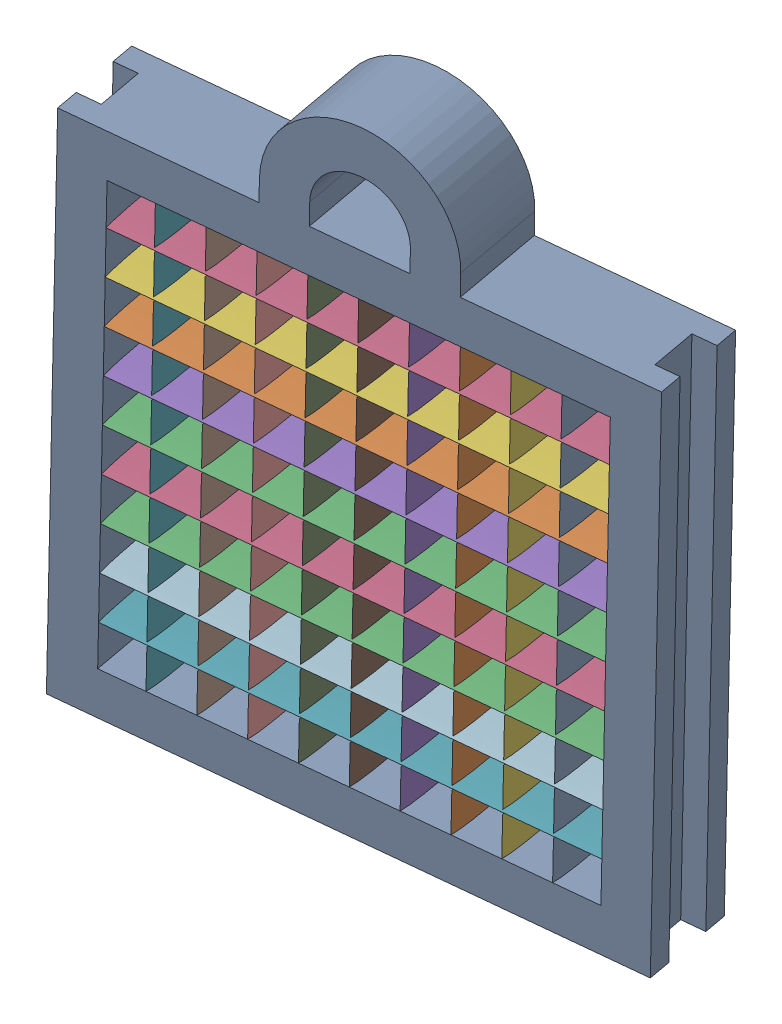
SolidWorks assembly Blade_assembly-2, configuration Default. Lengths in mm.
Overall size (128.96 151.07 42.39).
19 component instances, 2 part files, 0 mates.
Components (placement in the parent):
- Blade Frame-1-1: Blade Frame-1 [Default] at (771.0253 -161.3106 -497.9575) x (-0.987316 0.046404 0.151832) z (-0.150148 0.037854 -0.987939) size (120 145 20)
- Blade Piece-1-1: Blade Piece-1 [Default] at (675.8845 -87.1952 -480.658) x (0.051592 0.998205 0.030407) z (-0.150148 0.037854 -0.987939) size (1 100 20)
- Blade Piece-1-2: Blade Piece-1 [Default] at (674.8423 -107.3589 -481.2722) x (0.051592 0.998205 0.030407) z (-0.150148 0.037854 -0.987939) size (1 100 20)
- Blade Piece-1-3: Blade Piece-1 [Default] at (674.3212 -117.4408 -481.5793) x (0.051592 0.998205 0.030407) z (-0.150148 0.037854 -0.987939) size (1 100 20)
- Blade Piece-1-4: Blade Piece-1 [Default] at (731.1377 -159.4359 -491.8235) x (0.987316 -0.046404 -0.151832) z (0.150148 -0.037854 0.987939) size (1 100 20)
- Blade Piece-1-5: Blade Piece-1 [Default] at (676.4055 -77.1133 -480.3509) x (0.051592 0.998205 0.030407) z (-0.150148 0.037854 -0.987939) size (1 100 20)
- Blade Piece-1-6: Blade Piece-1 [Default] at (672.758 -147.6864 -482.5007) x (0.051592 0.998205 0.030407) z (-0.150148 0.037854 -0.987939) size (1 100 20)
- Blade Piece-1-7: Blade Piece-1 [Default] at (691.2502 -157.5612 -485.6895) x (0.987316 -0.046404 -0.151832) z (0.150148 -0.037854 0.987939) size (1 100 20)
- Blade Piece-1-8: Blade Piece-1 [Default] at (711.1939 -158.4986 -488.7565) x (0.987316 -0.046404 -0.151832) z (0.150148 -0.037854 0.987939) size (1 100 20)
- Blade Piece-1-9: Blade Piece-1 [Default] at (701.2221 -158.0299 -487.223) x (0.987316 -0.046404 -0.151832) z (0.150148 -0.037854 0.987939) size (1 100 20)
- Blade Piece-1-10: Blade Piece-1 [Default] at (721.1658 -158.9672 -490.29) x (0.987316 -0.046404 -0.151832) z (0.150148 -0.037854 0.987939) size (1 100 20)
- Blade Piece-1-11: Blade Piece-1 [Default] at (673.2791 -137.6045 -482.1935) x (0.051592 0.998205 0.030407) z (-0.150148 0.037854 -0.987939) size (1 100 20)
- Blade Piece-1-12: Blade Piece-1 [Default] at (761.0534 -160.8419 -496.424) x (0.987316 -0.046404 -0.151832) z (0.150148 -0.037854 0.987939) size (1 100 20)
- Blade Piece-1-13: Blade Piece-1 [Default] at (741.1096 -159.9046 -493.357) x (0.987316 -0.046404 -0.151832) z (0.150148 -0.037854 0.987939) size (1 100 20)
- Blade Piece-1-14: Blade Piece-1 [Default] at (673.8002 -127.5226 -481.8864) x (0.051592 0.998205 0.030407) z (-0.150148 0.037854 -0.987939) size (1 100 20)
- Blade Piece-1-15: Blade Piece-1 [Default] at (676.9266 -67.0314 -480.0438) x (0.051592 0.998205 0.030407) z (-0.150148 0.037854 -0.987939) size (1 100 20)
- Blade Piece-1-16: Blade Piece-1 [Default] at (675.3634 -97.277 -480.9651) x (0.051592 0.998205 0.030407) z (-0.150148 0.037854 -0.987939) size (1 100 20)
- Blade Piece-1-17: Blade Piece-1 [Default] at (751.0815 -160.3733 -494.8905) x (0.987316 -0.046404 -0.151832) z (0.150148 -0.037854 0.987939) size (1 100 20)
- Blade Piece-1-18: Blade Piece-1 [Default] at (681.2783 -157.0925 -484.156) x (0.987316 -0.046404 -0.151832) z (0.150148 -0.037854 0.987939) size (1 100 20)
